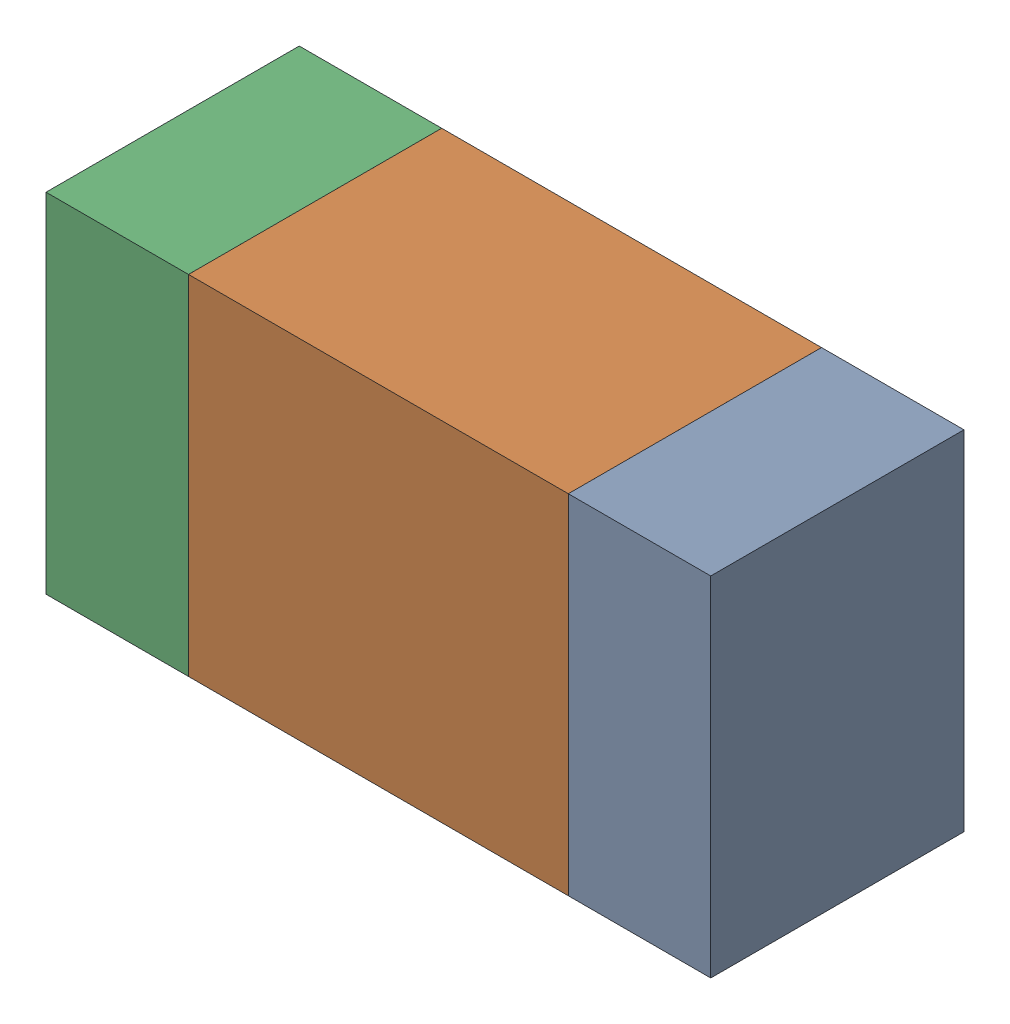
SolidWorks assembly R500_1PCB, configuration Default. Lengths in mm.
Overall size (1.05 0.55 0.4).
6 component instances, 2 part files, 0 mates.
Components (placement in the parent):
- 854785432-1: 854785432 [Default] at (155.8124 121.9999 0) size (0.22 0.55 0.4)
  - Extruded-1: Extruded [Default] at origin size (0.22 0.55 0.4)
- 854785568-1: 854785568 [Default] at (155.3999 121.9999 0) size (0.6 0.55 0.4)
  - Extruded_2-1: Extruded_2 [Default] at origin size (0.6 0.55 0.4)
- 854785432-2: 854785432 [Default] at (154.9874 121.9999 0) size (0.22 0.55 0.4)
  - Extruded-1: Extruded [Default] at origin size (0.22 0.55 0.4)
